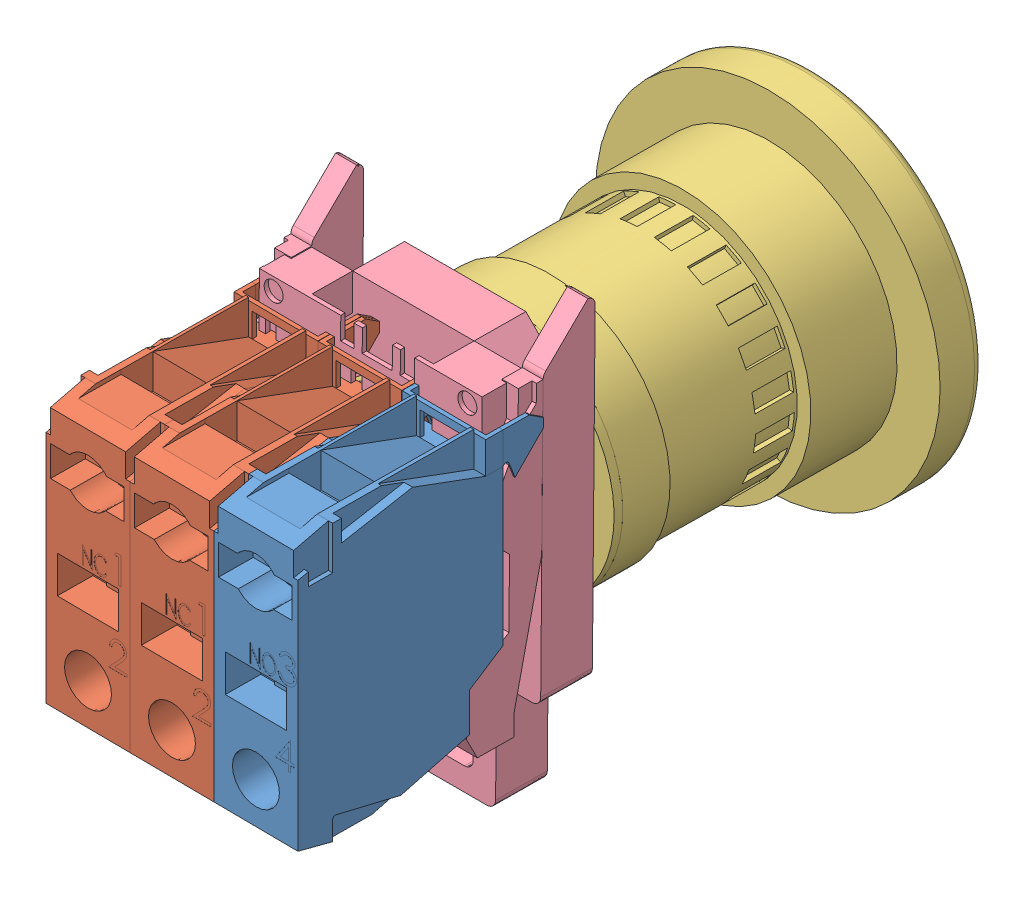
SolidWorks assembly E-Stop With Housing, configuration Default. Lengths in mm.
Overall size (45.45 51.34 77.34).
5 component instances, 4 part files, 3 mates.
Components (placement in the parent):
- NO Contact [ZBE-101]-1: NO Contact [ZBE-101] [Default] at (25.1307 1.9537 38.4865) x (-0.999962 0 -0.008727) z (0.008727 0 -0.999962) size (9.83 32 28.6)
- NC Contact [ZBE-102]-1: NC Contact [ZBE-102] [Default] at (5.4714 1.9537 38.3149) x (-0.999962 0 -0.008727) z (0.008727 0 -0.999962) size (9.83 32 28.6)
- NC Contact [ZBE-102]-2: NC Contact [ZBE-102] [Default] at (15.301 1.9537 38.4007) x (-0.999962 0 -0.008727) z (0.008727 0 -0.999962) size (9.83 32 28.6)
- E-Stop Button [ZB4BS844]-1: E-Stop Button [ZB4BS844] [Default] at (15.4382 1.4687 -30.594) x (-0.992649 0.121021 -0.001056) z (-0.121026 -0.992612 0.008662) size (40.81 55.91 40.81)
- Button Housing [ZB4BZ102]-1: Button Housing [ZB4BZ102] [Default] at (15.4523 0.1647 10.3057) x (1 0 0) z (0 0.999962 -0.008727) size (29.28 14.62 51.21)
Mates (geometry in assembly coordinates):
- Coincident1: coincident: point of NC Contact [ZBE-102]-1; point of NC Contact [ZBE-102]-2
- Coincident2: coincident: point of NO Contact [ZBE-101]-1; point of NC Contact [ZBE-102]-2
- Concentric3: concentric: cylinder of E-Stop Button [ZB4BS844]-1 through (15.4382 1.8395 11.9044) axis (0 -0.008727 -0.999962) radius 10.5; cylinder of Button Housing [ZB4BZ102]-1 through (15.4382 1.8255 10.3012) axis (0 -0.008727 -0.999962) radius 10.5
